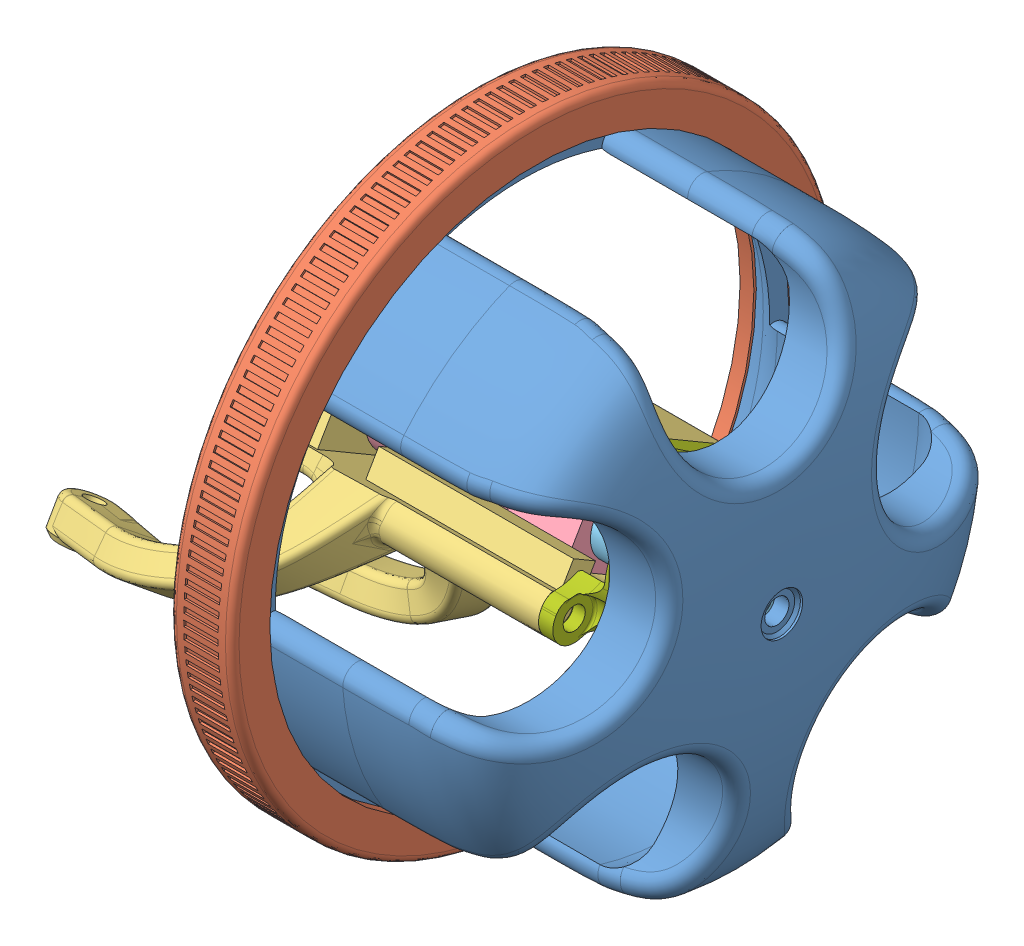
SolidWorks assembly Assem_wheel, configuration Default. Lengths in mm.
Overall size (77.85 85 85).
8 component instances, 7 part files, 4 mates.
Components (placement in the parent):
- SD-207 EduRover Wheel-1: SD-207 EduRover Wheel [Default] at (4.472 41.8816 66.9134) size (43.07 81.4 81.4)
- Pololu 90mm Tire-1: Pololu 90mm Tire [Default] at (5.2677 41.8816 66.9134) size (8.75 85 85)
- Assem_new-1: Assem_new [Default] at (51.9337 67.676 59.803) x (0 -0.504964 -0.86314) z (-1 0 0) size (48.17 38.87 74.84)
  - SD-209 Knuckle-1: SD-209 Knuckle [Default] at (7.0379 25.8547 67.2046) size (48.17 38.87 57.57)
  - newmotor-1: newmotor [Default] at (1.8879 19.8547 40.2046) x (-1 0 0) z (0 1 0) size (10 39 12)
  - spline adapter-1: spline adapter [Default] at (6.8879 25.8547 26.9446) x (-0.997189 0.074926 0) z (-0.074926 -0.997189 0) size (9.57 19.74 9.57)
  - WW bearing-1: WW bearing [Default] at (6.8879 25.8547 18.3246) size (16 16 4.95)
  - SD-204 Wheel Bearing Retainer-1: SD-204 Wheel Bearing Retainer [Default] at (7.0379 25.8547 27.9246) x (-1 0 0) z (0 0 -1) size (25.54 24 11.1)
Mates (geometry in assembly coordinates):
- Concentric1: concentric: cylinder of SD-207 EduRover Wheel-1 through (-995.3991 41.8816 66.9134) axis (-1 0 0) radius 40.7; cylinder of Pololu 90mm Tire-1 through (-994.7323 41.8816 66.9134) axis (-1 0 0) radius 40.7
- Coincident1: coincident: plane of SD-207 EduRover Wheel-1 through (7.722 79.0816 66.9134) normal (1 0 0); plane of Pololu 90mm Tire-1 through (7.722 81.7816 66.9134) normal (-1 0 0)
- Concentric2: concentric: cylinder of SD-207 EduRover Wheel-1 through (-995.3991 41.8816 66.9134) axis (-1 0 0) radius 1.7; cylinder of Assem_new-1/spline adapter-1 through (24.9891 41.8816 66.9134) axis (-1 0 0) radius 1.295
- Coincident2: coincident: plane of SD-207 EduRover Wheel-1 through (41.272 43.5816 66.9134) normal (-1 0 0); plane of Assem_new-1/spline adapter-1 through (41.272 41.8816 66.9134) normal (1 0 0)
